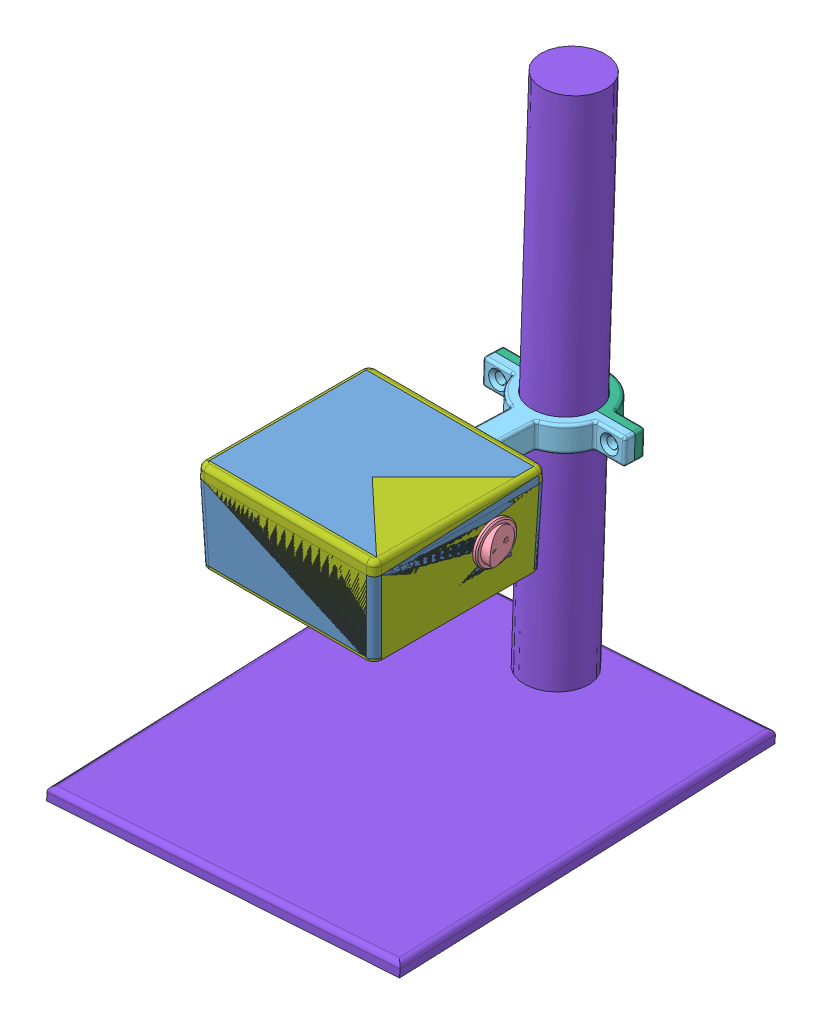
SolidWorks assembly AssemV2, configuration Default. Lengths in mm.
Overall size (141.24 212.77 176.11).
16 component instances, 15 part files, 21 mates.
Components (placement in the parent):
- Bottom_part-1: Bottom_part [Default] at (14.4897 15.0365 56.1161) x (0 0 1) z (0 1 0) size (68.1 70.1 35.14)
- PCB1.step-1: PCB1.step [Default] at (-35.3314 22.1939 -102.9335) x (0 0 1) z (0 1 0) size (39.77 55.94 13.33)
- POT10K.step-1: POT10K.step [Default] at (-4.845 33.6939 66.7447) x (0 1 0) z (-1 0 0) size (25.5 17 24.2)
- Button v5.step-1: Button v5.step [Default] at (31.5635 34.6391 38.0043) x (0.034899 0.999391 0) z (0 0 -1) size (16.3 23.9 17)
- Joint-2: Joint [Default] at (14.4897 26.5776 -19.4126) x (0 -0.034899 -0.999391) z (0 0.999391 -0.034899) size (42.1 56 10)
- Joint_part-3: Joint_part [Default] at (14.4897 36.5715 -19.7615) x (0 -0.034899 -0.999391) z (0 -0.999391 0.034899) size (16.7 56 10)
- Bottom-3: Bottom [Default] at (14.4897 15.0365 56.1161) x (0 0 1) z (0 1 0) size (68.1 70.1 35)
- base-1: base [Default] at (14.4897 -55.7302 -16.5383) x (0.997379 -0.002525 -0.07231) z (0 0.999391 -0.034899) size (130 160 207)
- LI-OV5640-MIPI-AF-1: LI-OV5640-MIPI-AF [Default] at (23.3278 17.8346 56.8556) x (0 0 -1) z (0.017452 -0.999848 0) size (10 36.25 5.61)
  - User Library-LI-OV5640-MIPI-AF_Designator1-1: User Library-LI-OV5640-MIPI-AF_Designator1 [Default] at origin size (5.9 3.96 1.31)
  - User Library-LI-OV5640-MIPI-AF_942681200-1: User Library-LI-OV5640-MIPI-AF_942681200 [Default] at origin size (6 6 5.26)
  - User Library-LI-OV5640-MIPI-AF_942681064-1: User Library-LI-OV5640-MIPI-AF_942681064 [Default] at origin size (2 2 5.26)
  - User Library-LI-OV5640-MIPI-AF_942680928-1: User Library-LI-OV5640-MIPI-AF_942680928 [Default] at origin size (8.5 8.5 5.25)
  - User Library-LI-OV5640-MIPI-AF_942680792-1: User Library-LI-OV5640-MIPI-AF_942680792 [Default] at origin size (10 11 0.35)
  - User Library-LI-OV5640-MIPI-AF_942680656-1: User Library-LI-OV5640-MIPI-AF_942680656 [Default] at origin size (8.5 10.5 0.35)
  - User Library-LI-OV5640-MIPI-AF_942676304-1: User Library-LI-OV5640-MIPI-AF_942676304 [Default] at origin size (10 36.25 0.15)
Mates (geometry in assembly coordinates):
- Coincident1: coincident anti-aligned: plane of Bottom_part-1 through (35.6616 21.7825 40.8305) normal (0 1 0); plane of PCB1.step-1 through (12.6695 21.7825 56.3919) normal (0 -1 0)
- Concentric1: concentric anti-aligned: circle of Bottom-1; circle of PCB1.step-1
- Concentric2: concentric anti-aligned: circle of Bottom-1; circle of PCB1.step-1
- Coincident6: coincident anti-aligned: plane of PCB1.step-1 through (12.6695 22.1939 56.3919) normal (0 1 0); plane of POT10K.step-1 through (-10.845 22.1939 59.1447) normal (0 -1 0)
- Perpendicular1: perpendicular: plane of Bottom_part-1 through (46.5583 17.0365 77.1848) normal (0 -0.034899 -0.999391); plane of POT10K.step-1 through (-4.845 33.6939 66.7447) normal (1 0 0)
- Coincident9: coincident anti-aligned: plane of Bottom_part-1 through (48.4897 15.0365 23.1161) normal (0.999391 -0.034899 0); plane of Button v5.step-1 through (49.1528 34.0249 42.7543) normal (-0.999391 0.034899 0)
- Concentric5: concentric aligned: circle of Bottom-1; circle of Joint-1
- Concentric7: concentric aligned: circle of Bottom-1; circle of Joint-1
- Concentric8: concentric anti-aligned: circle of Bottom-1; circle of Joint-1
- Coincident10: coincident anti-aligned: plane of Bottom_part-1 through (48.4897 15.0365 23.1161) normal (0 -0.034899 -0.999391); plane of Joint_part-1 through (-0.5103 68.2878 21.2566) normal (0 0.034899 0.999391)
- Coincident13: coincident anti-aligned: plane of Joint-2 through (14.4897 26.5776 -19.4126) normal (0 -0.034899 -0.999391); plane of Joint_part-3 through (14.4897 36.5715 -19.7615) normal (0 0.034899 0.999391)
- Concentric10: concentric anti-aligned: circle of Joint-2; circle of Joint_part-3
- Concentric11: concentric aligned: circle of Joint-2; circle of Joint_part-3
- Concentric18: concentric anti-aligned: circle of Bottom_part-1; circle of Bottom-3
- Concentric21: concentric anti-aligned: circle of Bottom_part-1; circle of Bottom-3
- Concentric22: concentric anti-aligned: circle of Bottom_part-1; circle of Bottom-3
- Concentric23: concentric aligned: circle of Bottom_part-1; circle of Bottom-3
- Coincident18: coincident anti-aligned: plane of Bottom_part-1 through (14.4897 45.0365 56.1161) normal (0 1 0); plane of Bottom-3 through (14.4897 45.0365 56.1161) normal (0 -1 0)
- Concentric24: concentric aligned: cylinder of Joint-2 through (14.4897 36.5715 -19.7615) axis (0 -0.999391 0.034899) radius 12.7; cylinder of base-1 through (14.4897 144.148 -23.5182) axis (0 -0.999391 0.034899) radius 12.5
- Concentric25: concentric anti-aligned: circle of Joint_part-3; circle of base-1
- Coincident20: coincident anti-aligned: plane of Bottom_part-1 through (14.8404 17.0365 52.3056) normal (0.999848 0.017452 0); plane of LI-OV5640-MIPI-AF-1/User Library-LI-OV5640-MIPI-AF_942680928-1 through (14.8291 17.6863 52.6056) normal (-0.999848 -0.017452 0)
